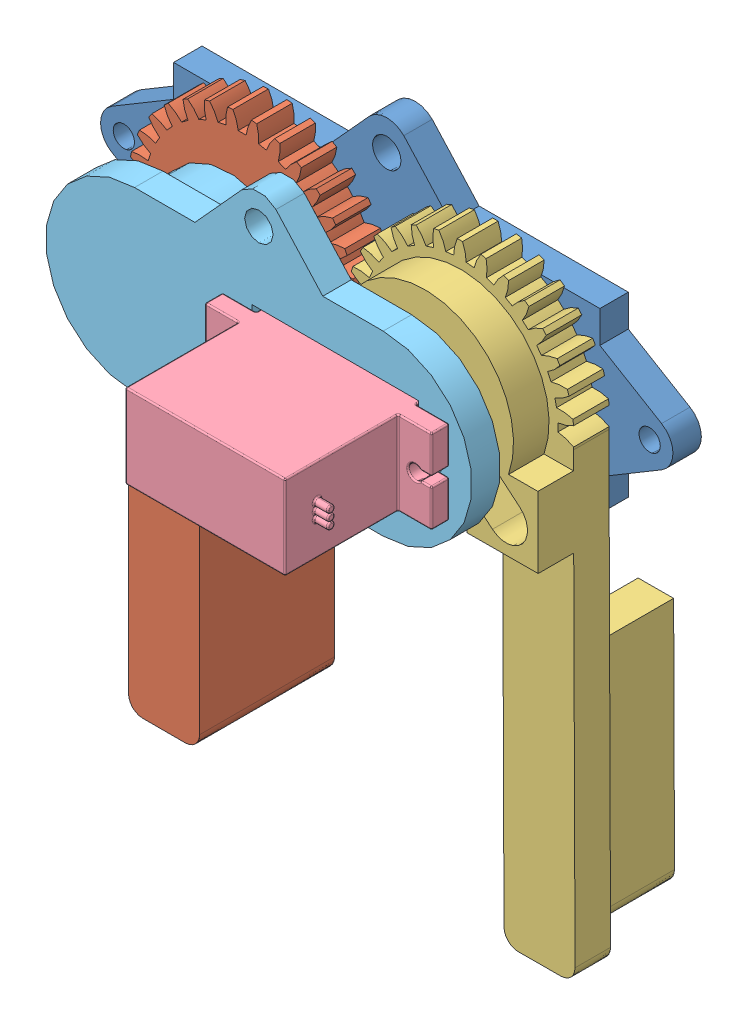
SolidWorks assembly Gripper, configuration Default. Lengths in mm.
Overall size (80.57 87.5 50.4).
5 component instances, 5 part files, 11 mates.
Components (placement in the parent):
- Gripper bottom plate-1: Gripper bottom plate [Default] at (52.9792 58.3634 36.6695) size (80.57 41.53 4)
- gripper-left-2: gripper-left [默认] at (25.2 56.8906 13.8691) x (0 0 -1) z (1 0 0) size (24 80.57 32.03)
- gripper-right-1: gripper-right [默认] at (69.7562 70.798 72.4698) x (0 0 1) z (0.003687 -0.999993 0) size (24 31.9 82.67)
- SG90-1: SG90 [默认] at (75.0792 64.2634 77.0695) x (0 -1 0) z (1 0 0) size (11.82 29.9 31.9)
- Gripper top plate-1: Gripper top plate [Default] at (52.9792 58.3634 58.6695) x (1 0 0) z (0 0 -1) size (60 41.53 11)
Mates (geometry in assembly coordinates):
- Concentric2: concentric: cylinder of Gripper bottom plate-1 through (37.6292 58.3634 40.6695) axis (0 0 -1) radius 7.8; cylinder of gripper-left-2 through (37.6292 58.3634 35.6695) axis (0 0 1) radius 7.5
- Coincident1: coincident: plane of Gripper bottom plate-1 through (15.9792 58.3634 40.6695) normal (0 0 1); plane of gripper-left-2 through (37.6292 58.3634 40.6695) normal (0 0 -1)
- Concentric3: concentric: cylinder of Gripper bottom plate-1 through (68.3292 58.3634 40.6695) axis (0 0 -1) radius 7.8; cylinder of gripper-right-1 through (68.3292 58.3634 35.6694) axis (0 0 1) radius 7.5
- Coincident2: coincident: plane of Gripper bottom plate-1 through (15.9792 58.3634 40.6695) normal (0 0 1); plane of gripper-right-1 through (68.3292 58.3634 40.6695) normal (0 0 -1)
- Concentric4: concentric: cylinder of gripper-left-2 through (37.6292 58.3634 50.6695) axis (0 0 -1) radius 7.5; cylinder of Gripper top plate-1 through (37.6292 58.3634 50.6695) axis (0 0 -1) radius 6.3775
- Concentric6: concentric: cylinder of Gripper bottom plate-1 through (52.9792 74.8634 40.6695) axis (0 0 -1) radius 2; cylinder of Gripper top plate-1 through (52.9792 74.8634 54.6695) axis (0 0 1) radius 2
- Concentric7: concentric: cylinder of Gripper bottom plate-1 through (52.9792 41.8634 40.6695) axis (0 0 -1) radius 2; cylinder of Gripper top plate-1 through (52.9792 41.8634 54.6695) axis (0 0 1) radius 2
- Concentric8: concentric: cylinder of SG90-1 through (77.4792 58.3634 77.0695) axis (0 0 -1) radius 1; cylinder of Gripper top plate-1 through (77.4792 58.3634 54.6695) axis (0 0 1) radius 1.25
- Coincident5: coincident: plane of SG90-1 through (79.7792 52.4634 58.6695) normal (0 0 -1); plane of Gripper top plate-1 through (70.4792 58.3634 58.6695) normal (0 0 1)
- Coincident6: coincident: plane of gripper-left-2 through (37.6292 58.3634 50.6695) normal (0 0 1); plane of Gripper top plate-1 through (37.6292 58.3634 50.6695) normal (0 0 -1)
- Parallel1: parallel: plane of SG90-1 through (75.0792 52.4634 77.0695) normal (0 -1 0); plane of Gripper top plate-1 through (51.9792 51.8634 54.6695) normal (0 1 0)
